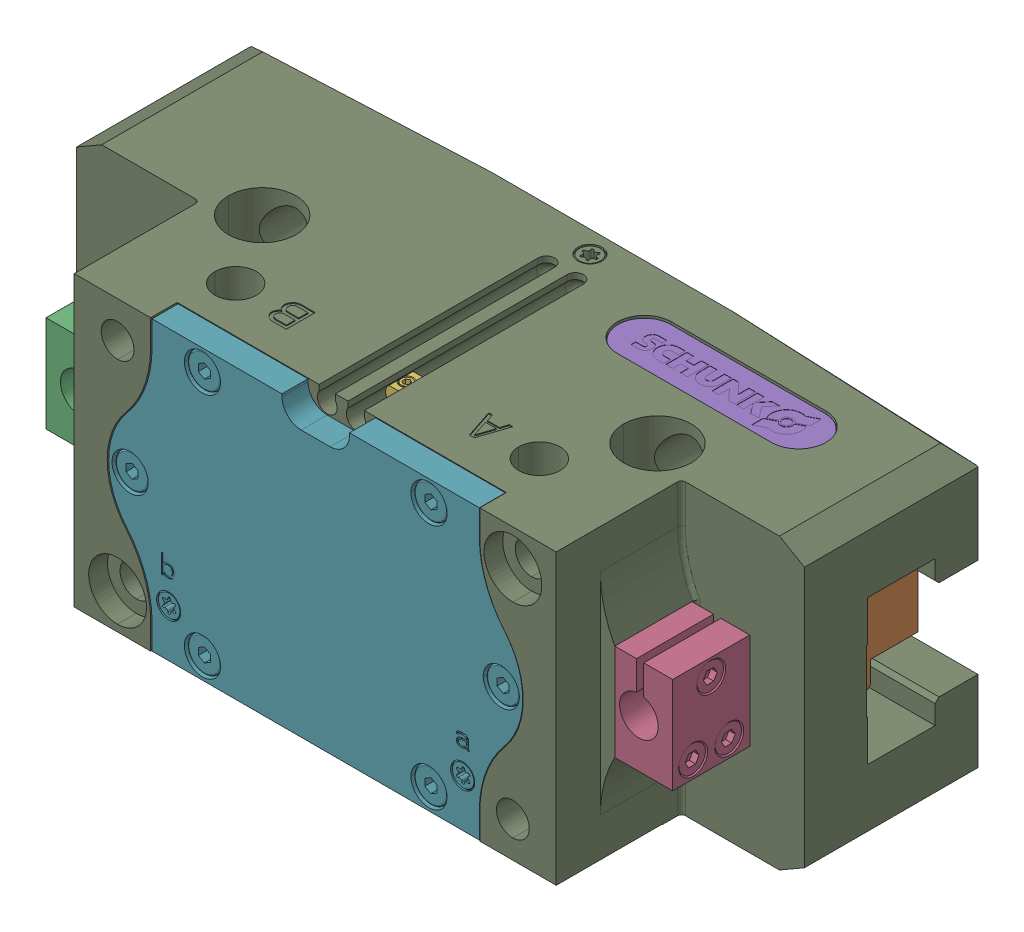
SolidWorks assembly SCHUNK_1460275_JGP_P_125_1_000ohne, configuration Default. Lengths in mm.
Overall size (151 60 63).
9 component instances, 7 part files, 0 mates.
Components (placement in the parent):
- SCHUNK_1460275_JGP_P_125_1_000ohne_3-1: SCHUNK_1460275_JGP_P_125_1_000ohne_3 [Default] at (-0.75 0 -39.1) x (0 1 0) z (-1 0 0) size (30 23.9 61.3)
- SCHUNK_1460275_JGP_P_125_1_000ohne_3-2: SCHUNK_1460275_JGP_P_125_1_000ohne_3 [Default] at (0.75 0 -39.1) x (0 -1 0) z (1 0 0) size (30 23.9 61.3)
- SCHUNK_1460275_JGP_P_125_1_000ohne_6-1: SCHUNK_1460275_JGP_P_125_1_000ohne_6 [Default] at (-53 0 -25.15) x (-1 0 0) z (0 1 0) size (12 16 20)
- SCHUNK_1460275_JGP_P_125_1_000ohne_6-2: SCHUNK_1460275_JGP_P_125_1_000ohne_6 [Default] at (53 0 -9.15) x (1 0 0) z (0 1 0) size (12 16 20)
- SCHUNK_1460275_JGP_P_125_1_000ohne_9-1: SCHUNK_1460275_JGP_P_125_1_000ohne_9 [Default] at (36.65 29.3 -47.65) x (1 0 0) z (0 1 0) size (43 11 0.3)
- SCHUNK_1460275_JGP_P_125_1_000ohne_11-1: SCHUNK_1460275_JGP_P_125_1_000ohne_11 [Default] at (3 26.125 -16) size (3.8 2.96 5)
- SCHUNK_1460275_JGP_P_125_1_000ohne_13-1: SCHUNK_1460275_JGP_P_125_1_000ohne_13 [Default] at (0 0 -5.5) x (-1 0 0) z (0 0 1) size (85.9 59.7 5.4)
- SCHUNK_1460275_JGP_P_125_1_000ohne_15-1: SCHUNK_1460275_JGP_P_125_1_000ohne_15 [Default] at (0 0 -61) x (0 -1 0) z (0 0 -1) size (56.8 43.3 6.15)
- SCHUNK_1460275_JGP_P_125_1_000ohne_17-1: SCHUNK_1460275_JGP_P_125_1_000ohne_17 [Default] x (1 0 0) z (0 1 0) size (151 62 60)
